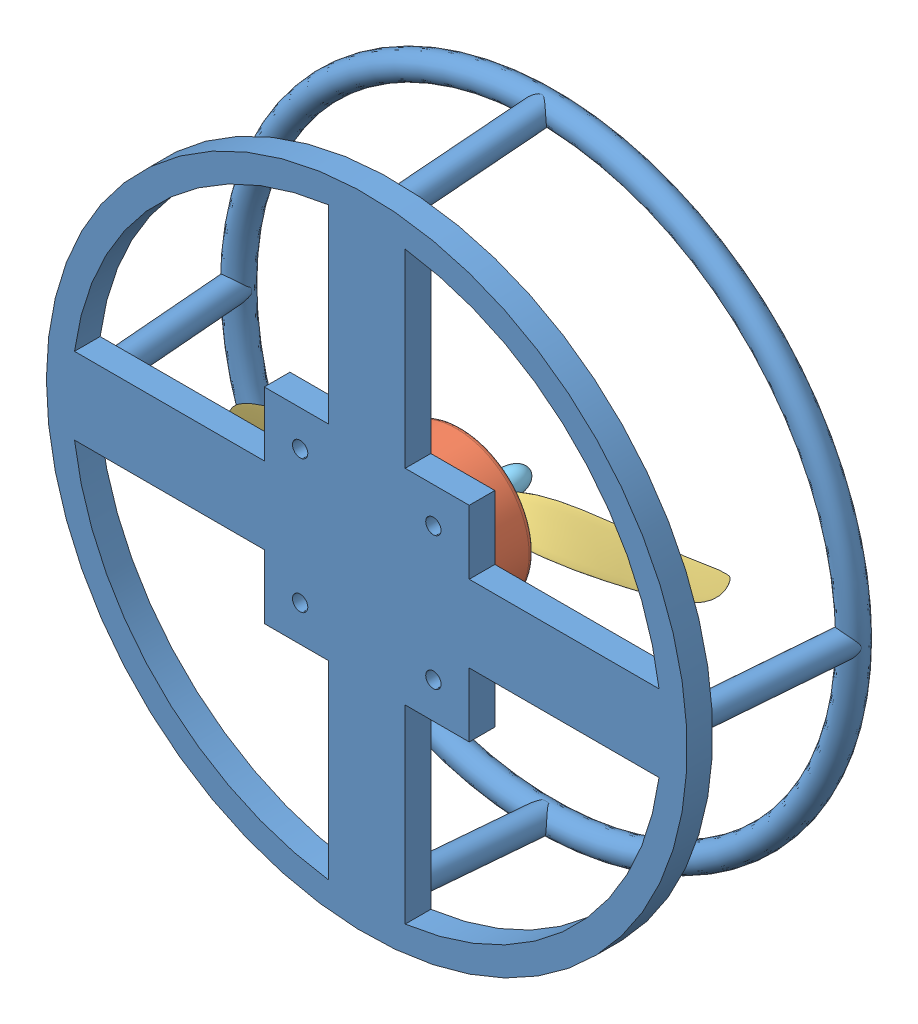
SolidWorks assembly propellers, configuration Default. Lengths in mm.
Overall size (125.2 125.2 37.5).
5 component instances, 5 part files, 10 mates.
Components (placement in the parent):
- propeller shield-1: propeller shield [Default] at (35.7674 59.3211 105.7949) size (125.2 125.2 37.5)
- motor-1: motor [Default] at (35.7674 59.3211 90.0261) x (1 0 0) z (0 1 0) size (28.43 25 28.43)
- aeronaut_cam_carbon_light_13x5.step-1: aeronaut_cam_carbon_light_13x5.step [Default] at (35.7659 59.3206 89.8554) x (0.983894 0.178751 0) z (0 0 1) size (100.1 9.42 3.24)
- M3 Nut-1: M3 Nut [Default] at (35.7674 59.3211 87.1925) x (0.707107 0.707107 0) z (0 0 1) size (5.5 6.35 2.74)
- tip-2: tip [Default] at (35.7674 59.3211 82.6885) x (-0.916245 0.400617 0) z (-0.400617 -0.916245 0) size (4.73 7 4.73)
Mates (geometry in assembly coordinates):
- Coincident1: coincident anti-aligned: plane of propeller shield-1 through (35.7674 59.3211 105.7949) normal (0 0 -1); plane of motor-1 through (35.7674 59.3211 105.7949) normal (0 0 1)
- Coincident2: coincident: line of assembly; axis of propeller shield-1 through (35.7674 59.3211 111.2215) axis (0 0 -1); axis of motor-1 through (35.7674 59.3211 90.7949) axis (0 0 -1)
- Concentric1: concentric anti-aligned: cylinder of motor-1 through (35.7674 59.3211 80.7949) axis (0 0 -1) radius 1.2; cylinder of aeronaut_cam_carbon_light_13x5.step-1 through (35.7674 59.3211 89.5937) axis (0 0 1) radius 1.2012
- Concentric2: concentric aligned: cylinder of motor-1 through (35.7674 59.3211 80.7949) axis (0 0 -1) radius 1.2; cylinder of tip-1 through (35.7674 59.3211 79.7949) axis (0 0 -1) radius 1.2
- Coincident4: coincident anti-aligned: plane of motor-1 through (36.9674 59.3211 80.7949) normal (0 0 -1); plane of tip-1 through (34.576 59.1783 80.7949) normal (0 0 1)
- Coincident6: coincident anti-aligned: plane of motor-1 through (36.9674 59.3211 90.7949) normal (0 0 -1); plane of aeronaut_cam_carbon_light_13x5.step-1 through (35.7674 59.3211 90.7949) normal (0 0 1)
- Coincident7: coincident: line of assembly; axis of propeller shield-1 through (35.7674 59.3211 111.2215) axis (0 0 -1); axis of M3 Nut-1 through (35.7674 59.3211 88.122) axis (0 0 -1)
- Coincident8: coincident anti-aligned: plane of aeronaut_cam_carbon_light_13x5.step-1 through (35.7674 59.3211 88.3925) normal (0 0 -1); plane of M3 Nut-1 through (35.7674 59.3211 88.3925) normal (0 0 1)
- Coincident9: coincident: axis of propeller shield-1 through (35.7674 59.3211 111.2215) axis (0 0 -1); axis of tip-2 through (35.7674 59.3211 80.9287) axis (0 0 -1)
- Coincident10: coincident anti-aligned: plane of M3 Nut-1 through (35.7674 59.3211 85.9925) normal (0 0 -1); plane of tip-2 through (34.668 59.8018 85.9925) normal (0 0 1)
